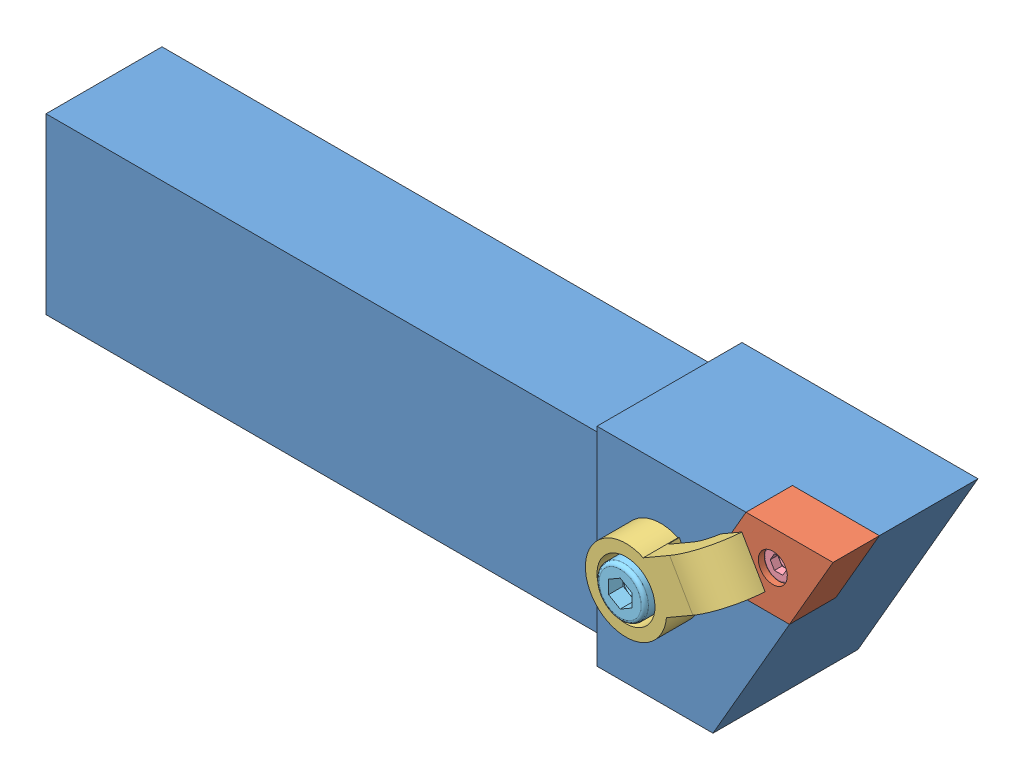
SolidWorks assembly 60度偏刀, configuration 默认. Lengths in mm.
Overall size (144.45 42.34 32).
5 component instances, 4 part files, 10 mates.
Components (placement in the parent):
- 60偏刀刀柄-1: 60偏刀刀柄 [默认] at (-21.8126 2.6791 0) size (140.7 35.85 25)
- 60度偏刀刀片-2: 60度偏刀刀片 [默认] at (57.6325 17.0289 17) x (0.866025 0.5 0) z (0 0 1) size (25.98 15 8)
- 60度偏刀挡片-1: 60度偏刀挡片 [默认] at (42.3835 13.9882 31) x (0.866025 0.5 0) z (0.5 -0.866025 0) size (25.45 12 14)
- hexagon socket head cap screws gb2-3: hexagon socket head cap screws gb2 [GB_FASTENER_SCREWS_HSHCS M3X5-N] at (58.5069 17.5337 24) x (0 0 -1) z (1 0 0) size (8 5.5 5.5)
- hexagon socket head cap screws gb2-4: hexagon socket head cap screws gb2 [GB_FASTENER_SCREWS_HSHCS M5X8-N] at (39.1874 7.5241 32) x (0 0 -1) z (0 -1 0) size (13 8.5 8.5)
Mates (geometry in assembly coordinates):
- 重合3: coincident anti-aligned: plane of 60偏刀刀柄-1 through (46.3825 10.5337 17) normal (0 1 0); plane of 60度偏刀刀片-2 through (46.3825 10.5337 25) normal (0 -1 0)
- 重合4: coincident anti-aligned: plane of 60偏刀刀柄-1 through (53.8825 23.5241 17) normal (0.866025 -0.5 0); plane of 60度偏刀刀片-2 through (53.8825 23.5241 25) normal (-0.866025 0.5 0)
- 重合5: coincident anti-aligned: plane of 60偏刀刀柄-1 through (-21.8126 2.6791 17) normal (0 0 1); plane of 60度偏刀刀片-2 through (57.6325 17.0289 17) normal (0 0 -1)
- 重合6: coincident anti-aligned: circle of 60偏刀刀柄-1; plane of 60度偏刀挡片-1 through (39.1874 7.5241 19) normal (0 0 -1)
- 同心2: concentric aligned: cylinder of 60偏刀刀柄-1 through (39.1874 7.5241 25) axis (0 0 1) radius 5; cylinder of 60度偏刀挡片-1 through (39.1874 7.5241 31) axis (0 0 1) radius 5
- 角度1: planar angle = 0.523599 rad aligned: plane of 60度偏刀挡片-1 through (50.7137 9.56 23.3699) normal (0.5 -0.866025 0); plane of 60偏刀刀柄-1 through (48.1874 -12.3209 0) normal (0.866025 -0.5 0)
- 同心3: concentric aligned: cylinder of 60度偏刀刀片-2 through (58.5069 17.5337 25) axis (0 0 1) radius 1.5; cylinder of hexagon socket head cap screws gb-3 through (58.5069 17.5337 16) axis (0 0 1) radius 1.5
- 重合7: coincident anti-aligned: plane of 60度偏刀刀片-2 through (59.8059 18.2837 21) normal (0 0 1); plane of hexagon socket head cap screws gb-3 through (58.5069 17.5337 21) normal (0 0 -1)
- 同心5: concentric aligned: cylinder of 60度偏刀挡片-1 through (39.1874 7.5241 31) axis (0 0 1) radius 2.5; cylinder of hexagon socket head cap screws gb-4 through (39.1874 7.5241 19) axis (0 0 1) radius 2.5
- 重合8: coincident anti-aligned: plane of 60度偏刀挡片-1 through (41.3525 8.7741 27) normal (0 0 1); plane of hexagon socket head cap screws gb-4 through (39.1874 7.5241 27) normal (0 0 -1)
